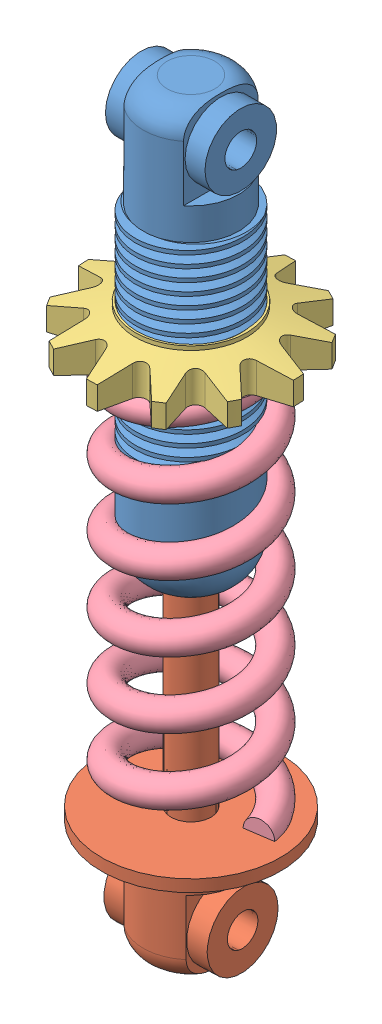
SolidWorks assembly Assem1, configuration Default. Lengths in mm.
Overall size (60.78 190.86 60.78).
4 component instances, 4 part files, 7 mates.
Components (placement in the parent):
- UpperBody-1: UpperBody [Default] at (31.907 7.3769 84.8327) size (28.39 109.38 27.68)
- Base-2: Base [Default] at (31.907 -45.65 84.8327) x (-0.999254 0 0.038614) z (-0.038614 0 -0.999254) size (45 101.45 45)
- Screw-1: Screw [Default] at (31.907 57.2726 84.8327) x (0.219679 0 -0.975572) z (0.975572 0 0.219679) size (50.85 11.87 50.85)
- Spring-2: Spring [Default] at (118.568 -57.867 71.8019) x (0.988883 0 -0.148694) z (0.148694 0 0.988883) size (38.1 106.92 37)
Mates (geometry in assembly coordinates):
- Concentric2: concentric aligned: cylinder of UpperBody-1 through (31.907 77.3769 84.8327) axis (0 -1 0) radius 4; cylinder of Base-2 through (31.907 27.35 84.8327) axis (0 -1 0) radius 5
- Concentric3: concentric aligned: cylinder of UpperBody-1 through (31.907 88.3069 84.8327) axis (0 -1 0) radius 13.5; cylinder of Screw-1 through (31.907 67.2726 84.8327) axis (0 -1 0) radius 14
- Screw1: screw = 1 aligned: line of UpperBody-1 through (31.907 88.3069 84.8327) axis (0 -1 0); line of Screw-1 through (31.907 67.2726 84.8327) axis (0 -1 0)
- Concentric6: concentric aligned: cylinder of UpperBody-1 through (31.907 77.3769 84.8327) axis (0 -1 0) radius 4; cylinder of Base-2 through (31.907 27.35 84.8327) axis (0 -1 0) radius 5
- Concentric7: concentric anti-aligned: cylinder of Screw-1 through (31.907 67.2726 84.8327) axis (0 -1 0) radius 14; line of Spring-2 through (31.907 -42.65 84.8327) axis (0 1 0)
- Coincident9: coincident anti-aligned: plane of Screw-1 through (31.907 57.2726 84.8327) normal (0 -1 0); plane of Spring-2 through (53.4726 57.2726 103.8373) normal (0 1 0)
- Coincident10: coincident anti-aligned: plane of Base-2 through (31.907 -42.65 84.8327) normal (0 1 0); plane of Spring-2 through (45.2944 -42.65 49.4487) normal (0 -1 0)
